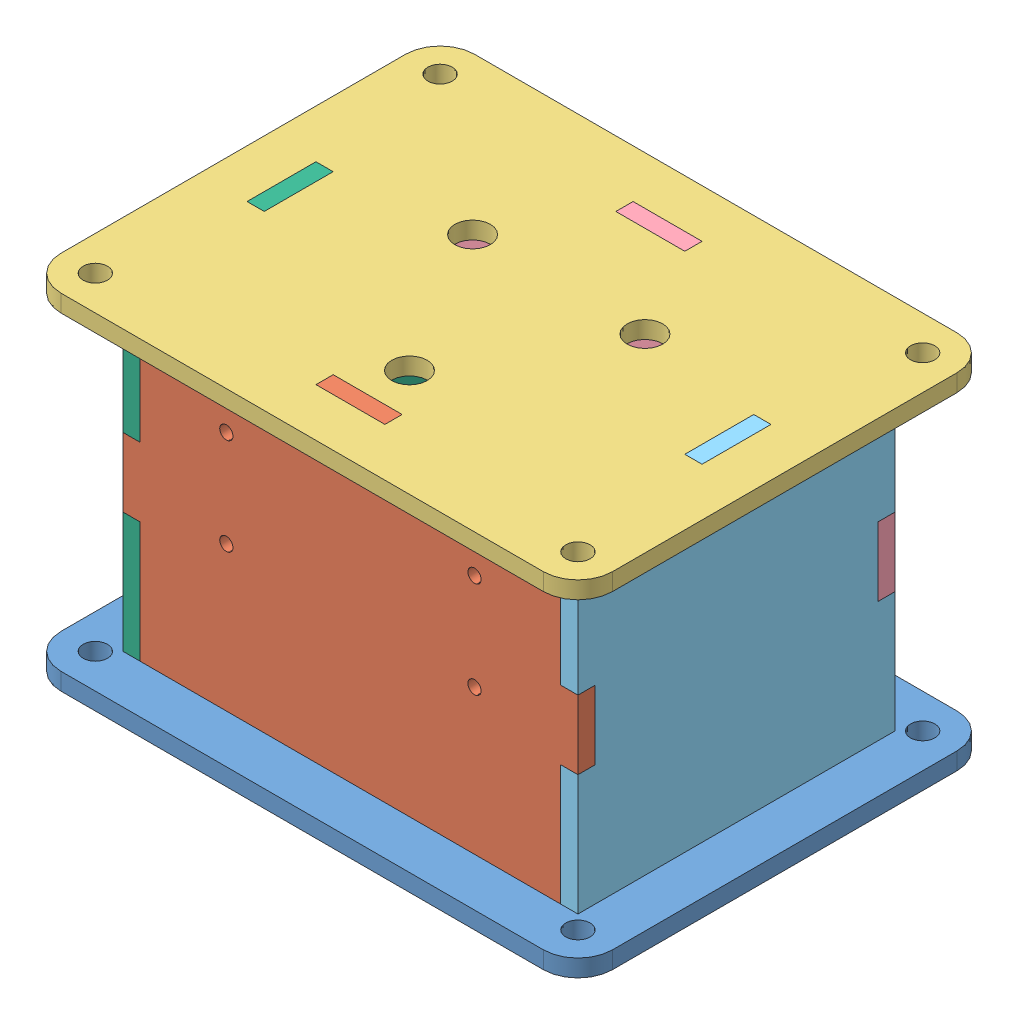
SolidWorks assembly Enclosure, configuration Default. Lengths in mm.
Overall size (101.6 63.5 76.2).
6 component instances, 6 part files, 15 mates.
Components (placement in the parent):
- Bottom-1: Bottom [Default] at (36.7184 56.1871 108.8983) size (101.6 3.17 76.2)
- Front-1: Front [Default] at (36.7184 87.9371 134.9333) size (83.82 63.5 3.17)
- Top-1: Top [Default] at (36.7184 116.5121 108.8983) size (101.6 3.17 76.2)
- Back-1: Back [Default] at (36.7184 87.9371 79.6883) size (83.82 63.5 3.17)
- Left-1: Left [Default] at (75.4534 87.9371 108.8983) size (3.17 63.5 58.42)
- Right-1: Right [Default] at (-5.1916 87.9371 108.8983) size (3.17 63.5 58.42)
Mates (geometry in assembly coordinates):
- Coincident1: coincident: plane of Bottom-1 through (36.7184 59.3621 108.8983) normal (0 1 0); plane of Front-1 through (43.0684 59.3621 138.1083) normal (0 -1 0)
- Coincident2: coincident: plane of Bottom-1 through (36.7184 56.1871 138.1083) normal (0 0 -1); plane of Front-1 through (36.7184 87.9371 138.1083) normal (0 0 1)
- Coincident3: coincident: plane of Bottom-1 through (43.0684 56.1871 138.1083) normal (-1 0 0); plane of Front-1 through (43.0684 56.1871 138.1083) normal (1 0 0)
- Coincident4: coincident: plane of Front-1 through (36.7184 87.9371 134.9333) normal (0 0 -1); plane of Top-1 through (43.0684 116.5121 134.9333) normal (0 0 1)
- Coincident5: coincident: plane of Front-1 through (43.0684 119.6871 138.1083) normal (1 0 0); plane of Top-1 through (43.0684 116.5121 138.1083) normal (-1 0 0)
- Coincident6: coincident: plane of Front-1 through (-2.0166 116.5121 138.1083) normal (0 1 0); plane of Top-1 through (36.7184 116.5121 108.8983) normal (0 -1 0)
- Coincident7: coincident: plane of Top-1 through (43.0684 116.5121 82.8633) normal (0 0 -1); plane of Back-1 through (36.7184 87.9371 82.8633) normal (0 0 1)
- Coincident8: coincident: plane of Top-1 through (30.3684 116.5121 82.8633) normal (1 0 0); plane of Back-1 through (30.3684 116.5121 82.8633) normal (-1 0 0)
- Coincident9: coincident: plane of Top-1 through (36.7184 116.5121 108.8983) normal (0 -1 0); plane of Back-1 through (43.0684 116.5121 82.8633) normal (0 1 0)
- Coincident10: coincident: plane of Bottom-1 through (75.4534 56.1871 115.2483) normal (0 0 -1); plane of Left-1 through (78.6284 56.1871 115.2483) normal (0 0 1)
- Coincident11: coincident: plane of Bottom-1 through (36.7184 56.1871 108.8983) normal (0 -1 0); plane of Left-1 through (78.6284 56.1871 102.5483) normal (0 -1 0)
- Coincident13: coincident: plane of Bottom-1 through (78.6284 56.1871 108.8983) normal (-1 0 0); plane of Left-1 through (78.6284 87.9371 108.8983) normal (1 0 0)
- Coincident14: coincident: plane of Bottom-1 through (-2.0166 56.1871 115.2483) normal (0 0 -1); plane of Right-1 through (-2.0166 56.1871 115.2483) normal (0 0 1)
- Coincident15: coincident: plane of Bottom-1 through (36.7184 56.1871 108.8983) normal (0 -1 0); plane of Right-1 through (-2.0166 56.1871 102.5483) normal (0 -1 0)
- Coincident16: coincident: plane of Bottom-1 through (-2.0166 56.1871 102.5483) normal (-1 0 0); plane of Right-1 through (-2.0166 87.9371 108.8983) normal (1 0 0)
